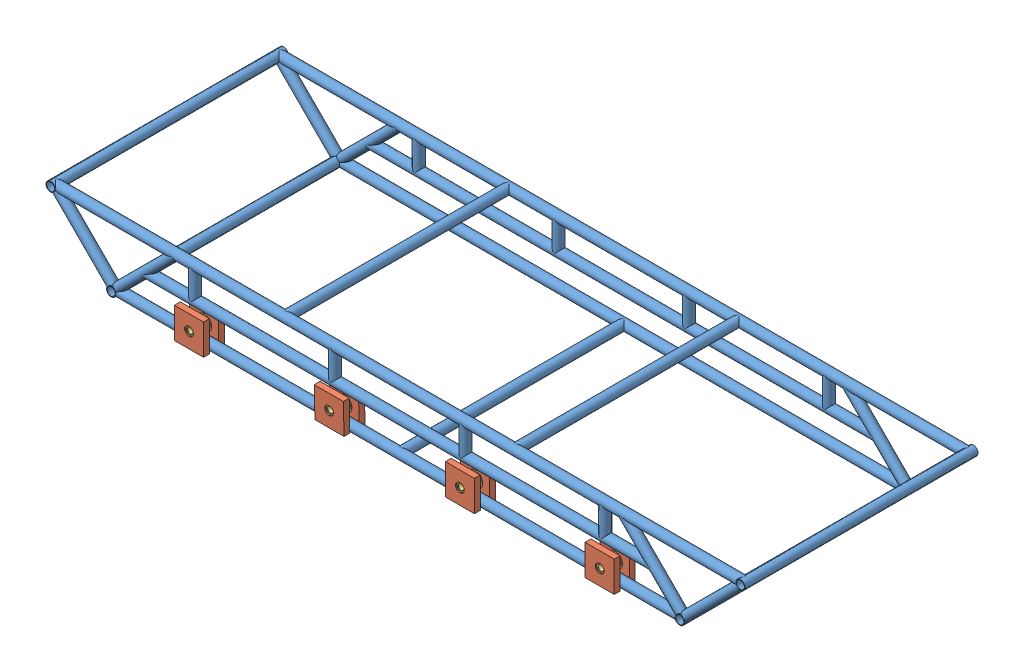
SolidWorks assembly Bodenwanne, configuration Standard. Lengths in mm.
Overall size (1200 120.5 410).
25 component instances, 3 part files, 24 mates.
Components (placement in the parent):
- Ramen Bodenwanne-1: Ramen Bodenwanne [Standard<Wie bearbeitet>] at (-1765.5754 89.1394 1497.5) size (1200 120 400)
- Lagerklotz-1: Lagerklotz [Standard] at (-1453.8766 3.3198 1432) size (50 52.5 10)
  - Lagerklotz-1: Lagerklotz [Standard] at (-89.1989 -26.6804 47.5) size (50 52.5 10)
  - radial ball bearing_68_din-1: radial ball bearing_68_din [DIN 625 - 6000 - 8,DE,NC,8_68] at (-64.1989 -0.4304 53.5) x (0 0 -1) z (1 0 0) size (8 26 26)
- Lagerklotz-2: Lagerklotz [Standard] at (-1213.9871 4.5623 1431.2898) x (1 0 0) z (0 -0.021338 0.999772) size (50 52.5 10)
  - Lagerklotz-1: Lagerklotz [Standard] at (-89.1989 -26.6804 47.5) size (50 52.5 10)
  - radial ball bearing_68_din-1: radial ball bearing_68_din [DIN 625 - 6000 - 8,DE,NC,8_68] at (-64.1989 -0.4304 53.5) x (0 0 -1) z (1 0 0) size (8 26 26)
- Lagerklotz-3: Lagerklotz [Standard] at (-988.8766 3.3198 1432) size (50 52.5 10)
  - Lagerklotz-1: Lagerklotz [Standard] at (-89.1989 -26.6804 47.5) size (50 52.5 10)
  - radial ball bearing_68_din-1: radial ball bearing_68_din [DIN 625 - 6000 - 8,DE,NC,8_68] at (-64.1989 -0.4304 53.5) x (0 0 -1) z (1 0 0) size (8 26 26)
- Lagerklotz-4: Lagerklotz [Standard] at (-748.8766 3.3198 1432) size (50 52.5 10)
  - Lagerklotz-1: Lagerklotz [Standard] at (-89.1989 -26.6804 47.5) size (50 52.5 10)
  - radial ball bearing_68_din-1: radial ball bearing_68_din [DIN 625 - 6000 - 8,DE,NC,8_68] at (-64.1989 -0.4304 53.5) x (0 0 -1) z (1 0 0) size (8 26 26)
- Lagerklotz-5: Lagerklotz [Standard] at (-1582.2743 3.3198 1563) x (-1 0 0) z (0 0 -1) size (50 52.5 10)
  - Lagerklotz-1: Lagerklotz [Standard] at (-89.1989 -26.6804 47.5) size (50 52.5 10)
  - radial ball bearing_68_din-1: radial ball bearing_68_din [DIN 625 - 6000 - 8,DE,NC,8_68] at (-64.1989 -0.4304 53.5) x (0 0 -1) z (1 0 0) size (8 26 26)
- Lagerklotz-6: Lagerklotz [Standard] at (-1342.3849 3.9862 1562.3073) x (-1 0 0) z (0 0.021338 -0.999772) size (50 52.5 10)
  - Lagerklotz-1: Lagerklotz [Standard] at (-89.1989 -26.6804 47.5) size (50 52.5 10)
  - radial ball bearing_68_din-1: radial ball bearing_68_din [DIN 625 - 6000 - 8,DE,NC,8_68] at (-64.1989 -0.4304 53.5) x (0 0 -1) z (1 0 0) size (8 26 26)
- Lagerklotz-7: Lagerklotz [Standard] at (-1117.2743 3.3198 1563) x (-1 0 0) z (0 0 -1) size (50 52.5 10)
  - Lagerklotz-1: Lagerklotz [Standard] at (-89.1989 -26.6804 47.5) size (50 52.5 10)
  - radial ball bearing_68_din-1: radial ball bearing_68_din [DIN 625 - 6000 - 8,DE,NC,8_68] at (-64.1989 -0.4304 53.5) x (0 0 -1) z (1 0 0) size (8 26 26)
- Lagerklotz-8: Lagerklotz [Standard] at (-877.2743 3.3198 1563) x (-1 0 0) z (0 0 -1) size (50 52.5 10)
  - Lagerklotz-1: Lagerklotz [Standard] at (-89.1989 -26.6804 47.5) size (50 52.5 10)
  - radial ball bearing_68_din-1: radial ball bearing_68_din [DIN 625 - 6000 - 8,DE,NC,8_68] at (-64.1989 -0.4304 53.5) x (0 0 -1) z (1 0 0) size (8 26 26)
Mates (geometry in assembly coordinates):
- Abstand14: distance = 8 mm: plane of Lagerklotz-1/Lagerklotz-1 through (-1543.0754 -23.3606 1489.5) normal (0 0 1); line of Ramen Bodenwanne-1 through (-1609.5754 37.1394 1497.5) axis (1 0 0)
- Abstand15: distance = 8 mm: plane of Lagerklotz-2/Lagerklotz-1 through (-1303.186 -23.339 1488.2074) normal (0 -0.021338 0.999772); line of Ramen Bodenwanne-1 through (-1609.5754 37.1394 1497.5) axis (1 0 0)
- Abstand16: distance = 8 mm: plane of Lagerklotz-3/Lagerklotz-1 through (-1078.0754 -23.3606 1489.5) normal (0 0 1); line of Ramen Bodenwanne-1 through (-1609.5754 37.1394 1497.5) axis (1 0 0)
- Abstand17: distance = 8 mm: plane of Lagerklotz-4/Lagerklotz-1 through (-838.0754 -23.3606 1489.5) normal (0 0 1); line of Ramen Bodenwanne-1 through (-1609.5754 37.1394 1497.5) axis (1 0 0)
- Abstand18: distance = 8 mm: plane of Lagerklotz-8/Lagerklotz-1 through (-788.0754 -23.3606 1505.5) normal (0 0 -1); line of Ramen Bodenwanne-1 through (-1609.5754 37.1394 1497.5) axis (1 0 0)
- Abstand19: distance = 8 mm: plane of Lagerklotz-7/Lagerklotz-1 through (-1028.0754 -23.3606 1505.5) normal (0 0 -1); line of Ramen Bodenwanne-1 through (-1609.5754 37.1394 1497.5) axis (1 0 0)
- Abstand20: distance = 8 mm: plane of Lagerklotz-6/Lagerklotz-1 through (-1253.186 -21.4612 1504.2511) normal (0 0.021338 -0.999772); line of Ramen Bodenwanne-1 through (-1609.5754 37.1394 1497.5) axis (1 0 0)
- Abstand21: distance = 8 mm: plane of Lagerklotz-5/Lagerklotz-1 through (-1493.0754 -23.3606 1505.5) normal (0 0 -1); line of Ramen Bodenwanne-1 through (-1609.5754 37.1394 1497.5) axis (1 0 0)
- Abstand1: distance = 7.5 mm: line of ? through (-1543.0754 29.1394 1497.5) axis (1 0 0); line of Ramen Bodenwanne-1 through (-1510.5754 36.6394 1497.5) axis (1 0 0)
- Abstand2: distance = 7.5 mm: line of ? through (-1303.0754 29.1394 1497.5) axis (1 0 0); line of Ramen Bodenwanne-1 through (-1270.5754 36.6394 1497.5) axis (1 0 0)
- Abstand3: distance = 7.5 mm: line of ? through (-1078.0754 29.1394 1497.5) axis (1 0 0); line of Ramen Bodenwanne-1 through (-1045.5754 36.6394 1497.5) axis (1 0 0)
- Abstand4: distance = 7.5 mm: line of ? through (-838.0754 29.1394 1497.5) axis (1 0 0); line of Ramen Bodenwanne-1 through (-805.5754 36.6394 1497.5) axis (1 0 0)
- Abstand5: distance = 7.5 mm: line of ? through (-788.0754 29.1394 1487.5) axis (-1 0 0); line of Ramen Bodenwanne-1 through (-1045.5754 36.6394 1487.5) axis (1 0 0)
- Abstand6: distance = 7.5 mm: line of ? through (-1028.0754 29.1394 1487.5) axis (-1 0 0); line of Ramen Bodenwanne-1 through (-1270.5754 36.6394 1487.5) axis (1 0 0)
- Abstand7: distance = 7.5 mm: line of ? through (-1253.0754 29.1394 1487.5) axis (-1 0 0); line of Ramen Bodenwanne-1 through (-1510.5754 36.6394 1487.5) axis (1 0 0)
- Abstand8: distance = 7.5 mm: line of ? through (-1493.0754 29.1394 1487.5) axis (-1 0 0); line of Ramen Bodenwanne-1 through (-1578.0754 36.6394 1487.5) axis (1 0 0)
- Abstand10: distance = 222.5 mm: line of ? through (-1543.0754 -23.3606 1497.5) axis (0 1 0); point of Ramen Bodenwanne-1
- Abstand11: distance = 462.5 mm: line of ? through (-1303.0754 -23.3606 1497.5) axis (0 1 0); point of Ramen Bodenwanne-1
- Abstand12: distance = 462.5 mm: line of ? through (-1028.0754 29.1394 1497.5) axis (0 -1 0); point of Ramen Bodenwanne-1
- Abstand13: distance = 222.5 mm: line of ? through (-788.0754 29.1394 1497.5) axis (0 -1 0); point of Ramen Bodenwanne-1
- Deckungsgleich27: coincident aligned: plane of Lagerklotz-4/Lagerklotz-1 through (-788.0754 29.1394 1489.5) normal (1 0 0); plane of Lagerklotz-8/Lagerklotz-1 through (-788.0754 29.1394 1505.5) normal (1 0 0)
- Deckungsgleich28: coincident aligned: plane of Lagerklotz-3/Lagerklotz-1 through (-1028.0754 29.1394 1489.5) normal (1 0 0); plane of Lagerklotz-7/Lagerklotz-1 through (-1028.0754 29.1394 1505.5) normal (1 0 0)
- Deckungsgleich29: coincident aligned: plane of Lagerklotz-2/Lagerklotz-1 through (-1253.186 29.149 1489.3276) normal (1 0 0); plane of Lagerklotz-6/Lagerklotz-1 through (-1253.186 31.0269 1505.3714) normal (1 0 0)
- Deckungsgleich30: coincident aligned: plane of Lagerklotz-1/Lagerklotz-1 through (-1493.0754 29.1394 1489.5) normal (1 0 0); plane of Lagerklotz-5/Lagerklotz-1 through (-1493.0754 29.1394 1505.5) normal (1 0 0)
